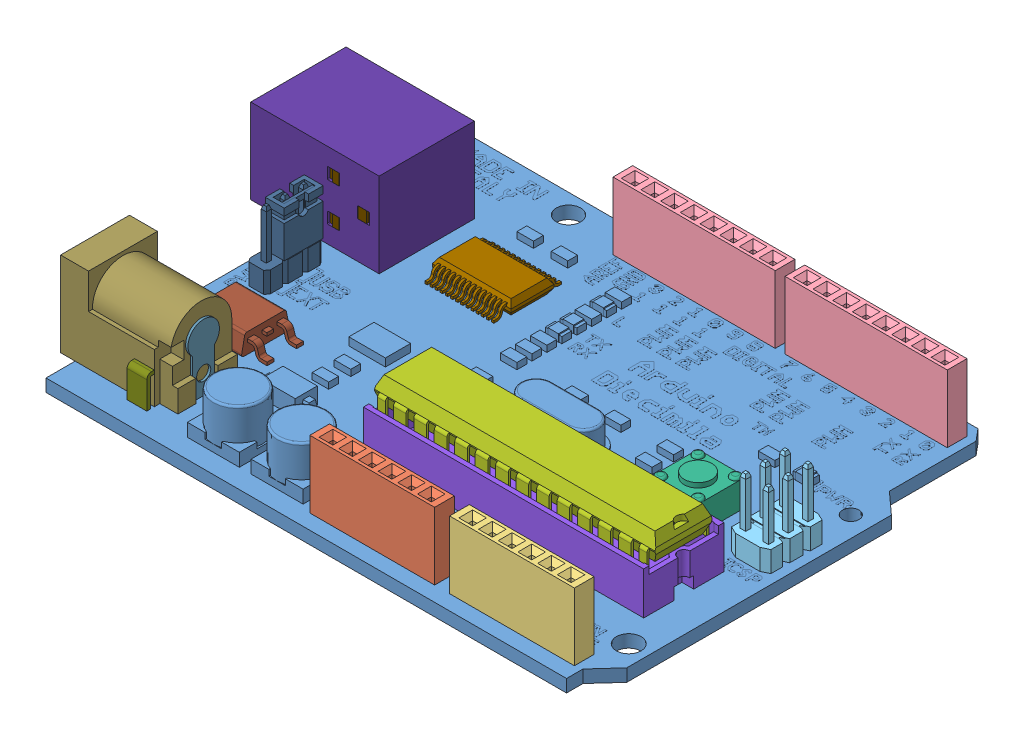
SolidWorks assembly Arduino_Diecimila_T8730, configuration Default. Lengths in mm.
Overall size (75.35 14.97 53.6).
25 component instances, 19 part files, 0 mates.
Components (placement in the parent):
- Arduino Diecimila PCB Board-1: Arduino Diecimila PCB Board [Default] x (-1 0 0) z (0 0 1) size (68.75 7.3 53.6)
- 2.5mm Pitch Miniature Socket - Power-1: 2.5mm Pitch Miniature Socket - Power [Default] at (5.15 0 23.65) x (-1 0 0) z (0 1 0) size (15.85 2.5 8.55)
- 2.5mm Pitch Miniature Socket - Analog Input-1: 2.5mm Pitch Miniature Socket - Analog Input [Default] at (22.9 0 23.65) x (1 0 0) z (0 1 0) size (15.85 2.5 8.55)
- 2.5mm Pitch Miniature Socket - Digital-1: 2.5mm Pitch Miniature Socket - Digital [Default] at (-1.625 0 -24) x (1 0 0) z (0 1 0) size (20.6 2.5 8.55)
- 2.5mm Pitch Miniature Socket - Digital-2: 2.5mm Pitch Miniature Socket - Digital [Default] at (20.225 0 -24) x (1 0 0) z (0 1 0) size (20.6 2.5 8.55)
- ICSP Header-1: ICSP Header [Default] at (30.675 0 -0.95) x (-1 0 0) z (0 1 0) size (5 7.4 8.8)
- Reset Button-1: Reset Button [Default] at (21.25 0 -0.375) x (-1 0 0) z (0 1 0) size (6.05 6.05 3.95)
- Microcontroller-1: Microcontroller [Default] at (12.175 4.9 10.1981) x (-1 0 0) z (0 1 0) size (35.6 7.9 3.98)
- Microcontroller Hub-1: Microcontroller Hub [Default] at (12.175 0 10.15) x (-1 0 0) z (0 1 0) size (35.6 10.2 5.4)
- FTDI USB Chip-1: FTDI USB Chip [Default] at (-16.325 0 -11.925) x (-1 0 0) z (0 1 0) size (10 8.58 1.8)
- Power Selection Jumper-1: Power Selection Jumper [Default] at (-30.675 0 0.15) x (-1 0 0) z (0 1 0) size (2.6 7.3 8.75)
- Voltage Regulator-1: Voltage Regulator [Default] at (-27.275 0 9.1282) x (-1 0 0) z (0 1 0) size (9.95 6.07 2.5)
- 2.1mm DC Power Socket-1: 2.1mm DC Power Socket [Default] at (-32.675 0 18.725) x (1 0 0) z (0 1 0) size (14.2 9.7 14.75)
  - 2.1mm DC Power Socket Housing-1: 2.1mm DC Power Socket Housing [Default] x (-1 0 0) z (0 0 1) size (14.2 8.75 10.75)
  - 2.1mm DC Power Socket Pin-1: 2.1mm DC Power Socket Pin [Default] at (5.8 0 6.4) x (0 1 0) z (-1 0 0) size (3.45 3.45 8.5)
  - Terminal 1-1: Terminal 1 [Default] at (9.95 0 6.4) x (0 1 0) z (1 0 0) size (4 12 0.3)
  - Terminal 2-1: Terminal 2 [Default] at (2.95 0 0) x (1 0 0) z (0 0 -1) size (0.4 2.8 4)
  - Terminal 3-1: Terminal 3 [Default] at (5.85 -4.375 4.05) x (0 1 0) z (1 0 0) size (0.95 7.9 2.5)
- USB Series B Receptacle-1: USB Series B Receptacle [Default] at (-40.675 5.375 -11.85) x (0 0 1) z (-1 0 0) size (14.85 14.97 16.3)
  - USB Series B Receptacle Metal Shell-1: USB Series B Receptacle Metal Shell [Default] x (-1 0 0) z (0 0 1) size (14.85 14.97 16.3)
  - USB Series B Receptacle Housing-1: USB Series B Receptacle Housing [Default] at (0 0 -15.7) x (-1 0 0) z (0 0 1) size (12.1 10.45 15.7)
  - USB Series B Receptacle Terminal-1: USB Series B Receptacle Terminal [Default] at (-0.575 1.075 -8.5) x (-1 0 0) z (0 1 0) size (1.35 12.17 0.84)
  - USB Series B Receptacle Terminal-2: USB Series B Receptacle Terminal [Default] at (1.925 1.075 -8.5) x (-1 0 0) z (0 1 0) size (1.35 12.17 0.84)
  - USB Series B Receptacle Terminal-3: USB Series B Receptacle Terminal [Default] at (-1.925 -1.475 -8.5) x (1 0 0) z (0 -1 0) size (1.35 12.17 0.84)
  - USB Series B Receptacle Terminal-4: USB Series B Receptacle Terminal [Default] at (0.575 -1.475 -8.5) x (1 0 0) z (0 -1 0) size (1.35 12.17 0.84)
